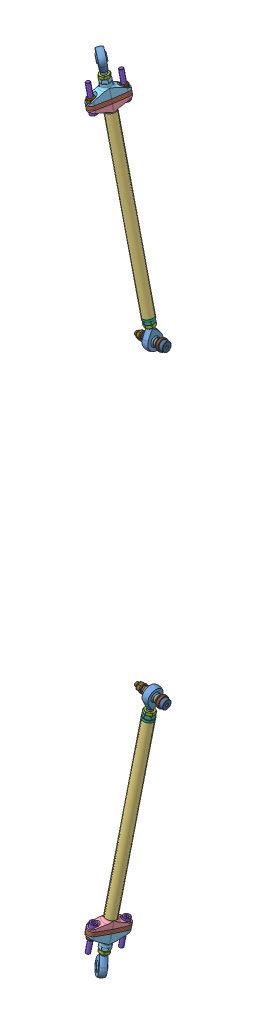
SolidWorks assembly PUTM-S-SR-Tierod, configuration Domyślna. Lengths in mm.
Overall size (83.91 1206.07 71.19).
44 component instances, 12 part files, 43 mates.
Components (placement in the parent):
- PUTM-S-rodend-1: PUTM-S-rodend [8mm] at (-1575.5246 548.2039 164.4433) x (-0.589908 -0.14356 0.794607) z (-0.797606 -0.049753 -0.601123) size (12 54 24)
- PUTM-S-rodend-2: PUTM-S-rodend [8mm] at (-1540.2782 271.5119 140.5803) x (0.991864 0.123602 0.030459) z (0.019569 0.088385 -0.995894) size (12 54 24)
- PUTM-S-SR-DS-Shims-1: PUTM-S-SR-DS-Shims [2mm] at (-1574.5654 540.6872 163.7958) x (-0.30039 -0.119874 0.946254) z (0.125898 -0.988374 -0.085244) size (54 15.5 2)
- PUTM-S-SR-DS-Shims-2: PUTM-S-SR-DS-Shims [2mm] at (-1574.3136 538.7104 163.6253) x (-0.30039 -0.119874 0.946254) z (0.125898 -0.988374 -0.085244) size (54 15.5 2)
- PUTM-S-SR-DS-Shims-3: PUTM-S-SR-DS-Shims [2mm] at (-1573.81 534.7569 163.2843) x (-0.30039 -0.119874 0.946254) z (-0.125898 0.988374 0.085244) size (54 15.5 2)
- PUTM-S-SR-Tierod-Tube-1: PUTM-S-SR-Tierod-Tube [Domyślna] at (-1566.6324 478.4082 158.4244) x (0.867513 0.151368 -0.473823) z (0.125898 -0.988374 -0.085244) size (15.5 15.5 264.92)
- PUTM-S-SR-Tierod-Insert-shims-1: PUTM-S-SR-Tierod-Insert-shims [Domyślna] at (-1573.81 534.7569 163.2843) x (0.30039 0.119874 -0.946254) z (-0.945471 -0.093525 -0.31199) size (54 51.81 17.91)
- PUTM-S-SR-DS-Insert-shims-2-1: PUTM-S-SR-DS-Insert-shims-2 [M8] at (-1574.5654 540.6872 163.7958) x (0.30039 0.119874 -0.946254) z (0.945471 0.093525 0.31199) size (54 25 22.85)
- PUTM-S-Insert-M8-1: PUTM-S-Insert-M8 [M8] at (-1538.5928 258.2806 139.4392) x (-0.125898 0.988374 0.085244) z (-0.525937 0.00636 -0.850499) size (38.3 16.51 15.5)
- PUTM-S-DS-DIN-EN-ISO-4035-1: PUTM-S-DS-DIN-EN-ISO-4035 [M8_low] at (-1577.7145 565.3964 165.9261) x (0.93729 0.090357 0.336635) z (-0.125898 0.988374 0.085244) size (13 15.01 4)
- PUTM-S-DS-DIN-EN-ISO-4035-2: PUTM-S-DS-DIN-EN-ISO-4035 [M8_low] at (-1537.422 249.0888 138.6464) x (0.982556 0.136088 -0.126745) z (-0.125898 0.988374 0.085244) size (13 15.01 4)
- PUTM-FT-FABORY_ISO912-1: PUTM-FT-FABORY_ISO912 [M6x35 [07071.060.035]] at (-1578.8106 524.4525 181.5274) x (0.125898 -0.988374 -0.085244) z (-0.466577 -0.134824 0.874144) size (41 10 10)
- PUTM-FT-FABORY_ISO912-2: PUTM-FT-FABORY_ISO912 [M6x35 [07071.060.035]] at (-1566.795 529.2474 143.6773) x (0.125898 -0.988374 -0.085244) z (0.729319 0.033965 0.68333) size (41 10 10)
- PUTM-FT-FABORY_DIN985-1: PUTM-FT-FABORY_DIN985 [M6 [12348.060.001]] at (-1580.825 540.2664 182.8913) x (-0.668607 -0.021057 -0.743318) z (-0.125898 0.988374 0.085244) size (11.9 10.35 6.18)
- PUTM-FT-FABORY_DIN985-2: PUTM-FT-FABORY_DIN985 [M6 [12348.060.001]] at (-1568.8094 545.0614 145.0412) x (-0.30039 -0.119874 0.946254) z (-0.125898 0.988374 0.085244) size (11.9 10.35 6.18)
- PUTM-FT-ELESA_ISO7379-1: PUTM-FT-ELESA_ISO7379 [8-M6-30] at (-1513.402 232.1499 137) x (0.995082 0.099052 0) z (-0.006575 0.066053 0.997794) size (46.5 13 13)
- PUTM-FT-FABORY_ISO7089-2: PUTM-FT-FABORY_ISO7089 [M6 [38093.060.001]] at (-1548.1801 228.688 137) x (0.009811 -0.098565 0.995082) z (-0.995082 -0.099052 0) size (12 12 1.6)
- PUTM-FT-FABORY_DIN985-5: PUTM-FT-FABORY_DIN985 [M6 [12348.060.001]] at (-1549.7723 228.5295 137) x (-0.006309 0.063382 0.997969) z (-0.995082 -0.099052 0) size (11.9 10.35 6.18)
- PUTM-FT-FABORY_ISO7089-1: PUTM-FT-FABORY_ISO7089 [M8 [38093.080.001]] at (-1518.875 231.6051 137) x (0.009811 -0.098565 0.995082) z (-0.995082 -0.099052 0) size (16 16 1.6)
- PUTM-FT-FABORY_ISO7089-3: PUTM-FT-FABORY_ISO7089 [M8 [38093.080.001]] at (-1520.4671 231.4466 137) x (0.009811 -0.098565 0.995082) z (-0.995082 -0.099052 0) size (16 16 1.6)
- PUTM-FT-FABORY_DIN985-3: PUTM-FT-FABORY_DIN985 [M6 [12348.060.001]] at (-1580.825 -540.2664 182.8913) x (0.668607 -0.021057 0.743318) z (-0.125898 -0.988374 0.085244) size (11.9 10.35 6.18)
- PUTM-FT-FABORY_DIN985-4: PUTM-FT-FABORY_DIN985 [M6 [12348.060.001]] at (-1568.8094 -545.0614 145.0412) x (0.30039 -0.119874 -0.946254) z (-0.125898 -0.988374 0.085244) size (11.9 10.35 6.18)
- PUTM-FT-FABORY_ISO912-3: PUTM-FT-FABORY_ISO912 [M6x35 [07071.060.035]] at (-1566.795 -529.2474 143.6773) x (0.125898 0.988374 -0.085244) z (-0.729319 0.033965 -0.68333) size (41 10 10)
- PUTM-S-DS-DIN-EN-ISO-4035-3: PUTM-S-DS-DIN-EN-ISO-4035 [M8_low] at (-1537.9256 -253.0423 138.9874) x (0.982556 -0.136088 -0.126745) z (0.125898 0.988374 -0.085244) size (13 15.01 4)
- PUTM-FT-FABORY_ISO912-4: PUTM-FT-FABORY_ISO912 [M6x35 [07071.060.035]] at (-1578.8106 -524.4525 181.5274) x (0.125898 0.988374 -0.085244) z (0.466577 -0.134824 -0.874144) size (41 10 10)
- PUTM-S-SR-DS-Shims-4: PUTM-S-SR-DS-Shims [2mm] at (-1574.3136 -538.7104 163.6253) x (-0.30039 0.119874 0.946254) z (-0.125898 -0.988374 0.085244) size (54 15.5 2)
- PUTM-S-SR-Tierod-Tube-2: PUTM-S-SR-Tierod-Tube [Domyślna] at (-1544.6616 -305.9245 143.5483) x (0.867513 -0.151368 -0.473823) z (-0.125898 -0.988374 0.085244) size (15.5 15.5 264.92)
- PUTM-S-SR-DS-Shims-5: PUTM-S-SR-DS-Shims [2mm] at (-1574.0618 -536.7337 163.4548) x (-0.30039 0.119874 0.946254) z (0.125898 0.988374 -0.085244) size (54 15.5 2)
- PUTM-S-SR-DS-Shims-6: PUTM-S-SR-DS-Shims [2mm] at (-1574.0618 -536.7337 163.4548) x (-0.30039 0.119874 0.946254) z (-0.125898 -0.988374 0.085244) size (54 15.5 2)
- PUTM-S-DS-DIN-EN-ISO-4035-4: PUTM-S-DS-DIN-EN-ISO-4035 [M8_low] at (-1578.2181 -569.3499 166.267) x (0.93729 -0.090357 0.336635) z (0.125898 0.988374 -0.085244) size (13 15.01 4)
- PUTM-S-Insert-M8-2: PUTM-S-Insert-M8 [M8] at (-1538.5928 -258.2806 139.4392) x (-0.125898 -0.988374 0.085244) z (0.525937 0.00636 0.850499) size (38.3 16.51 15.5)
- PUTM-S-SR-Tierod-Insert-shims-2: PUTM-S-SR-Tierod-Insert-shims [Domyślna] at (-1573.81 -534.7569 163.2843) x (0.30039 -0.119874 -0.946254) z (0.945471 -0.093525 0.31199) size (54 51.81 17.91)
- PUTM-S-rodend-3: PUTM-S-rodend [8mm] at (-1540.2782 -271.5119 140.5803) x (0.991864 -0.123602 0.030459) z (-0.019569 0.088385 0.995894) size (12 54 24)
- PUTM-S-rodend-4: PUTM-S-rodend [8mm] at (-1575.5246 -548.2039 164.4433) x (-0.589908 0.14356 0.794607) z (0.797606 -0.049753 0.601123) size (12 54 24)
- PUTM-S-SR-DS-Insert-shims-2-2: PUTM-S-SR-DS-Insert-shims-2 [M8] at (-1574.5654 -540.6872 163.7958) x (0.30039 -0.119874 -0.946254) z (-0.945471 0.093525 -0.31199) size (54 25 22.85)
- PUTM-S-SR-Tierod-Mush-1: PUTM-S-SR-Tierod-Mush [Domyślna] at (-1525.2933 230.9662 137) x (-0.995082 -0.099052 0) z (0.055867 -0.56124 -0.825765) size (3.75 12 12)
- PUTM-S-SR-Tierod-Mush-2: PUTM-S-SR-Tierod-Mush [Domyślna] at (-1544.6974 229.0347 137) x (0.995082 0.099052 0) z (0 0 1) size (3.75 12 12)
- PUTM-FT-ELESA_ISO7379-2: PUTM-FT-ELESA_ISO7379 [8-M6-30] at (-1513.402 -232.1499 137) x (0.995082 -0.099052 0) z (0.006575 0.066053 -0.997794) size (46.5 13 13)
- PUTM-FT-FABORY_ISO7089-4: PUTM-FT-FABORY_ISO7089 [M8 [38093.080.001]] at (-1520.4671 -231.4466 137) x (0.009811 0.098565 0.995082) z (0.995082 -0.099052 0) size (16 16 1.6)
- PUTM-FT-FABORY_ISO7089-5: PUTM-FT-FABORY_ISO7089 [M8 [38093.080.001]] at (-1522.0592 -231.2881 137) x (0.009811 0.098565 0.995082) z (0.995082 -0.099052 0) size (16 16 1.6)
- PUTM-S-SR-Tierod-Mush-3: PUTM-S-SR-Tierod-Mush [Domyślna] at (-1525.2933 -230.9662 137) x (-0.995082 0.099052 0) z (-0.055867 -0.56124 0.825765) size (3.75 12 12)
- PUTM-S-SR-Tierod-Mush-4: PUTM-S-SR-Tierod-Mush [Domyślna] at (-1544.6974 -229.0347 137) x (0.995082 -0.099052 0) z (0 0 -1) size (3.75 12 12)
- PUTM-FT-FABORY_DIN985-6: PUTM-FT-FABORY_DIN985 [M6 [12348.060.001]] at (-1549.7723 -228.5295 137) x (0.006309 0.063382 -0.997969) z (-0.995082 0.099052 0) size (11.9 10.35 6.18)
- PUTM-FT-FABORY_ISO7089-6: PUTM-FT-FABORY_ISO7089 [M6 [38093.060.001]] at (-1549.7723 -228.5295 137) x (0.009811 0.098565 0.995082) z (0.995082 -0.099052 0) size (12 12 1.6)
Mates (geometry in assembly coordinates):
- Koncentryczne7: concentric anti-aligned: cylinder of PUTM-S-SR-Tierod-Insert-shims-1 through (-1567.8022 537.1544 144.3592) axis (0.125898 -0.988374 -0.085244) radius 3; cylinder of PUTM-S-SR-DS-Insert-shims-2-1 through (-1568.5576 543.0847 144.8707) axis (-0.125898 0.988374 0.085244) radius 3
- Koncentryczne8: concentric anti-aligned: cylinder of PUTM-S-SR-Tierod-Insert-shims-1 through (-1579.8178 532.3595 182.2094) axis (0.125898 -0.988374 -0.085244) radius 3; cylinder of PUTM-S-SR-DS-Insert-shims-2-1 through (-1580.5732 538.2897 182.7209) axis (-0.125898 0.988374 0.085244) radius 3
- Wspólnie4: coincident anti-aligned: plane of PUTM-S-SR-DS-Insert-shims-2-1 through (-1577.7128 565.3965 165.9269) normal (-0.125898 0.988374 0.085244); plane of PUTM-S-DS-DIN-EN-ISO-4035-1 through (-1577.7145 565.3964 165.9261) normal (0.125898 -0.988374 -0.085244)
- Koncentryczne10: concentric aligned: cylinder of PUTM-S-SR-DS-Insert-shims-2-1 through (-1568.5576 543.0847 144.8707) axis (-0.125898 0.988374 0.085244) radius 3; cylinder of PUTM-S-SR-DS-Shims-1 through (-1568.3058 541.1079 144.7002) axis (-0.125898 0.988374 0.085244) radius 3
- Koncentryczne11: concentric aligned: cylinder of PUTM-S-SR-DS-Insert-shims-2-1 through (-1580.5732 538.2897 182.7209) axis (-0.125898 0.988374 0.085244) radius 3; cylinder of PUTM-S-SR-DS-Shims-1 through (-1580.3214 536.3129 182.5504) axis (-0.125898 0.988374 0.085244) radius 3
- Wspólnie5: coincident anti-aligned: plane of PUTM-S-SR-DS-Insert-shims-2-1 through (-1574.5654 540.6872 163.7958) normal (0.125898 -0.988374 -0.085244); plane of PUTM-S-SR-DS-Shims-1 through (-1574.5654 540.6872 163.7958) normal (-0.125898 0.988374 0.085244)
- Koncentryczne12: concentric aligned: cylinder of PUTM-S-SR-DS-Insert-shims-2-1 through (-1568.5576 543.0847 144.8707) axis (-0.125898 0.988374 0.085244) radius 3; cylinder of PUTM-S-SR-DS-Shims-2 through (-1568.054 539.1312 144.5297) axis (-0.125898 0.988374 0.085244) radius 3
- Koncentryczne13: concentric aligned: cylinder of PUTM-S-SR-DS-Insert-shims-2-1 through (-1580.5732 538.2897 182.7209) axis (-0.125898 0.988374 0.085244) radius 3; cylinder of PUTM-S-SR-DS-Shims-2 through (-1580.0696 534.3362 182.3799) axis (-0.125898 0.988374 0.085244) radius 3
- Wspólnie6: coincident anti-aligned: plane of PUTM-S-SR-DS-Shims-1 through (-1574.3136 538.7104 163.6253) normal (0.125898 -0.988374 -0.085244); plane of PUTM-S-SR-DS-Shims-2 through (-1574.3136 538.7104 163.6253) normal (-0.125898 0.988374 0.085244)
- Koncentryczne14: concentric anti-aligned: cylinder of PUTM-S-SR-DS-Shims-2 through (-1568.054 539.1312 144.5297) axis (-0.125898 0.988374 0.085244) radius 3; cylinder of PUTM-S-SR-DS-Shims-3 through (-1568.054 539.1312 144.5297) axis (0.125898 -0.988374 -0.085244) radius 3
- Koncentryczne15: concentric anti-aligned: cylinder of PUTM-S-SR-DS-Shims-2 through (-1580.0696 534.3362 182.3799) axis (-0.125898 0.988374 0.085244) radius 3; cylinder of PUTM-S-SR-DS-Shims-3 through (-1580.0696 534.3362 182.3799) axis (0.125898 -0.988374 -0.085244) radius 3
- Wspólnie7: coincident anti-aligned: plane of PUTM-S-SR-DS-Shims-2 through (-1574.0618 536.7337 163.4548) normal (0.125898 -0.988374 -0.085244); plane of PUTM-S-SR-DS-Shims-3 through (-1574.0618 536.7337 163.4548) normal (-0.125898 0.988374 0.085244)
- Wspólnie8: coincident anti-aligned: plane of PUTM-S-SR-Tierod-Insert-shims-1 through (-1573.81 534.7569 163.2843) normal (-0.125898 0.988374 0.085244); plane of PUTM-S-SR-DS-Shims-3 through (-1573.81 534.7569 163.2843) normal (0.125898 -0.988374 -0.085244)
- Wspólnie12: coincident anti-aligned: plane of PUTM-S-Insert-M8-1 through (-1537.9256 253.0423 138.9874) normal (0.125898 -0.988374 -0.085244); plane of PUTM-S-DS-DIN-EN-ISO-4035-2 through (-1537.9256 253.0423 138.9874) normal (-0.125898 0.988374 0.085244)
- Koncentryczne19: concentric anti-aligned: cylinder of PUTM-S-SR-Tierod-Insert-shims-1 through (-1567.8022 537.1544 144.3592) axis (0.125898 -0.988374 -0.085244) radius 3; cylinder of PUTM-FT-FABORY_ISO912-2 through (-1582.3004 650.9745 154.1759) axis (-0.125898 0.988374 0.085244) radius 3
- Koncentryczne20: concentric anti-aligned: cylinder of PUTM-S-SR-Tierod-Insert-shims-1 through (-1579.8178 532.3595 182.2094) axis (0.125898 -0.988374 -0.085244) radius 3; cylinder of PUTM-FT-FABORY_ISO912-1 through (-1594.316 646.1796 192.026) axis (-0.125898 0.988374 0.085244) radius 3
- Wspólnie13: coincident anti-aligned: plane of PUTM-S-SR-Tierod-Insert-shims-1 through (-1578.815 530.6824 179.6733) normal (0.125898 -0.988374 -0.085244); plane of PUTM-FT-FABORY_ISO912-1 through (-1575.1886 530.7341 184.4295) normal (-0.125898 0.988374 0.085244)
- Koncentryczne21: concentric anti-aligned: cylinder of PUTM-FT-FABORY_ISO912-2 through (-1582.3004 650.9745 154.1759) axis (-0.125898 0.988374 0.085244) radius 3; cylinder of PUTM-FT-FABORY_DIN985-2 through (-1569.3129 549.0149 145.3822) axis (0.125898 -0.988374 -0.085244) radius 3
- Wspólnie14: coincident anti-aligned: plane of PUTM-S-SR-DS-Insert-shims-2-1 through (-1569.5603 544.7617 147.4068) normal (-0.125898 0.988374 0.085244); plane of PUTM-FT-FABORY_DIN985-2 through (-1568.8094 545.0614 145.0412) normal (0.125898 -0.988374 -0.085244)
- Wspólnie15: coincident anti-aligned: plane of PUTM-S-SR-DS-Insert-shims-2-1 through (-1577.1833 567.0267 147.8075) normal (0.945471 0.093525 0.31199); plane of PUTM-FT-FABORY_DIN985-2 through (-1573.1731 548.8933 141.0906) normal (-0.945471 -0.093525 -0.31199)
- Koncentryczne22: concentric anti-aligned: cylinder of PUTM-FT-FABORY_ISO912-1 through (-1594.316 646.1796 192.026) axis (-0.125898 0.988374 0.085244) radius 3; cylinder of PUTM-FT-FABORY_DIN985-1 through (-1581.3286 544.2199 183.2323) axis (0.125898 -0.988374 -0.085244) radius 3
- Wspólnie16: coincident anti-aligned: plane of PUTM-S-SR-DS-Insert-shims-2-1 through (-1580.074 540.5661 180.5257) normal (-0.125898 0.988374 0.085244); plane of PUTM-FT-FABORY_DIN985-1 through (-1580.825 540.2664 182.8913) normal (0.125898 -0.988374 -0.085244)
- Wspólnie17: coincident anti-aligned: plane of PUTM-S-SR-DS-Insert-shims-2-1 through (-1578.2423 563.7664 184.0463) normal (-0.945471 -0.093525 -0.31199); plane of PUTM-FT-FABORY_DIN985-1 through (-1577.4684 544.3415 187.5239) normal (0.945471 0.093525 0.31199)
- Wspólnie18: coincident anti-aligned: plane of PUTM-S-SR-Tierod-Insert-shims-1 through (-1568.3014 534.878 146.5544) normal (0.125898 -0.988374 -0.085244); plane of PUTM-FT-FABORY_ISO912-2 through (-1564.1879 535.9187 140.5632) normal (-0.125898 0.988374 0.085244)
- Koncentryczne28: concentric anti-aligned: cylinder of PUTM-FT-ELESA_ISO7379-1 through (-1513.402 232.1499 137) axis (-0.995082 -0.099052 0) radius 4; cylinder of PUTM-FT-FABORY_ISO7089-1 through (-1520.4671 231.4466 137) axis (0.995082 0.099052 0) radius 4.2
- Wspólnie19: coincident anti-aligned: plane of PUTM-FT-ELESA_ISO7379-1 through (-1519.5174 238.0589 136.5685) normal (-0.995082 -0.099052 0); plane of PUTM-FT-FABORY_ISO7089-1 through (-1518.875 231.6051 137) normal (0.995082 0.099052 0)
- Koncentryczne29: concentric anti-aligned: cylinder of PUTM-FT-ELESA_ISO7379-1 through (-1513.402 232.1499 137) axis (-0.995082 -0.099052 0) radius 3; cylinder of PUTM-FT-FABORY_ISO7089-2 through (-1549.7723 228.5295 137) axis (0.995082 0.099052 0) radius 3.2
- Koncentryczne30: concentric anti-aligned: cylinder of PUTM-FT-ELESA_ISO7379-1 through (-1513.402 232.1499 137) axis (-0.995082 -0.099052 0) radius 3; cylinder of PUTM-FT-FABORY_DIN985-5 through (-1553.7526 228.1333 137) axis (0.995082 0.099052 0) radius 3
- Wspólnie20: coincident anti-aligned: plane of PUTM-FT-FABORY_ISO7089-2 through (-1549.7723 228.5295 137) normal (-0.995082 -0.099052 0); plane of PUTM-FT-FABORY_DIN985-5 through (-1549.7723 228.5295 137) normal (0.995082 0.099052 0)
- Koncentryczne31: concentric aligned: cylinder of PUTM-FT-ELESA_ISO7379-1 through (-1513.402 232.1499 137) axis (-0.995082 -0.099052 0) radius 4; cylinder of PUTM-S-SR-Tierod-Mush-2 through (-1544.6974 229.0347 137) axis (-0.995082 -0.099052 0) radius 4
- Koncentryczne32: concentric anti-aligned: cylinder of PUTM-FT-ELESA_ISO7379-1 through (-1513.402 232.1499 137) axis (-0.995082 -0.099052 0) radius 4; cylinder of PUTM-S-SR-Tierod-Mush-1 through (-1525.2933 230.9662 137) axis (0.995082 0.099052 0) radius 4
- Odległość3: distance = 3.5 mm anti-aligned: plane of PUTM-FT-FABORY_ISO7089-2 through (-1548.1801 228.688 137) normal (0.995082 0.099052 0); plane of PUTM-S-SR-Tierod-Mush-2 through (-1545.0936 233.015 137) normal (-0.995082 -0.099052 0)
- Koncentryczne33: concentric anti-aligned: cylinder of PUTM-FT-ELESA_ISO7379-1 through (-1513.402 232.1499 137) axis (-0.995082 -0.099052 0) radius 4; cylinder of PUTM-FT-FABORY_ISO7089-3 through (-1522.0592 231.2881 137) axis (0.995082 0.099052 0) radius 4.2
- Wspólnie26: coincident anti-aligned: plane of PUTM-FT-FABORY_ISO7089-1 through (-1520.4671 231.4466 137) normal (-0.995082 -0.099052 0); plane of PUTM-FT-FABORY_ISO7089-3 through (-1520.4671 231.4466 137) normal (0.995082 0.099052 0)
- Odległość4: distance = 3.25 mm anti-aligned: plane of PUTM-FT-FABORY_ISO7089-3 through (-1522.0592 231.2881 137) normal (-0.995082 -0.099052 0); plane of PUTM-S-SR-Tierod-Mush-1 through (-1525.6204 234.253 134.7439) normal (0.995082 0.099052 0)
- Concentric2: concentric anti-aligned: cylinder of PUTM-S-SR-Tierod-Tube-1 through (-1572.3235 523.087 162.2778) axis (0.125898 -0.988374 -0.085244) radius 6.35; cylinder of PUTM-S-SR-Tierod-Insert-shims-1 through (-1572.3235 523.087 162.2778) axis (-0.125898 0.988374 0.085244) radius 6.3
- Coincident4: coincident anti-aligned: plane of PUTM-S-SR-Tierod-Tube-1 through (-1572.3235 523.087 162.2778) normal (-0.125898 0.988374 0.085244); plane of PUTM-S-SR-Tierod-Insert-shims-1 through (-1572.3235 523.087 162.2778) normal (0.125898 -0.988374 -0.085244)
- Concentric3: concentric aligned: cylinder of PUTM-S-SR-Tierod-Tube-1 through (-1572.3235 523.087 162.2778) axis (0.125898 -0.988374 -0.085244) radius 6.35; cylinder of PUTM-S-Insert-M8-1 through (-1538.9705 261.2458 139.6949) axis (0.125898 -0.988374 -0.085244) radius 6.3
- Concentric4: concentric aligned: cylinder of PUTM-S-Insert-M8-1 through (-1538.5928 258.2806 139.4392) axis (0.125898 -0.988374 -0.085244) radius 4; cylinder of PUTM-S-DS-DIN-EN-ISO-4035-2 through (-1537.9256 253.0423 138.9874) axis (0.125898 -0.988374 -0.085244) radius 4
- Coincident5: coincident anti-aligned: plane of PUTM-S-SR-Tierod-Tube-1 through (-1538.9705 261.2458 139.6949) normal (0.125898 -0.988374 -0.085244); plane of PUTM-S-Insert-M8-1 through (-1533.6292 262.2104 136.3991) normal (-0.125898 0.988374 0.085244)
- Concentric5: concentric anti-aligned: cone of PUTM-S-rodend-2 through (-1537.1308 246.803 138.4493) axis (-0.125898 0.988374 0.085244); cylinder of PUTM-S-DS-DIN-EN-ISO-4035-2 through (-1537.9256 253.0423 138.9874) axis (0.125898 -0.988374 -0.085244) radius 4
- Concentric9: concentric aligned: cone of PUTM-S-rodend-1 through (-1578.6719 572.9128 166.5743) axis (0.125898 -0.988374 -0.085244); cylinder of PUTM-S-DS-DIN-EN-ISO-4035-1 through (-1578.2181 569.3499 166.267) axis (0.125898 -0.988374 -0.085244) radius 4
- Coincident11: coincident anti-aligned: plane of PUTM-S-SR-Tierod-Tube-1 through (-1538.9705 261.2458 139.6949) normal (0.125898 -0.988374 -0.085244); plane of PUTM-S-Insert-M8-1 through (-1533.6292 262.2104 136.3991) normal (-0.125898 0.988374 0.085244)
